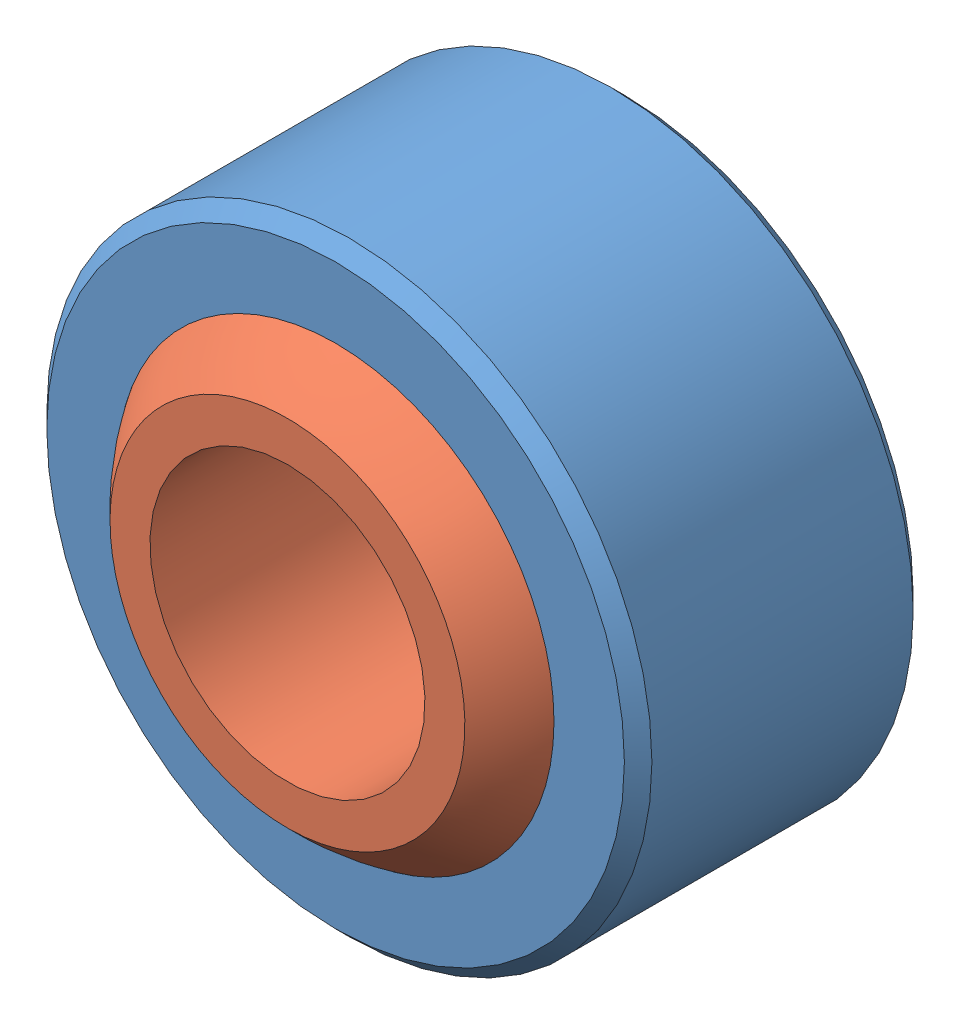
SolidWorks assembly Wide Spherical Bearing, configuration Default. Lengths in mm.
Overall size (26.86 26.86 14).
2 component instances, 2 part files, 2 mates.
Components (placement in the parent):
- Wide Bearing Cage-1: Wide Bearing Cage [Default] at (7.3247 13.3464 16.0877)
- Wide Ball-1: Wide Ball [Default] at (7.3247 13.3464 16.0877) x (0.753976 0.656902 0) z (0 0 1)
Mates (geometry in assembly coordinates):
- Concentric1: concentric: sphere of Wide Bearing Cage-1; sphere of Wide Ball-1
- LimitAngle1: limit planar angle = 0 rad aligned: plane of Wide Ball-1 through (7.3247 13.3464 16.0877) normal (0 0 1); plane of Wide Bearing Cage-1 through (7.3247 13.3464 16.0877) normal (0 0 1)
